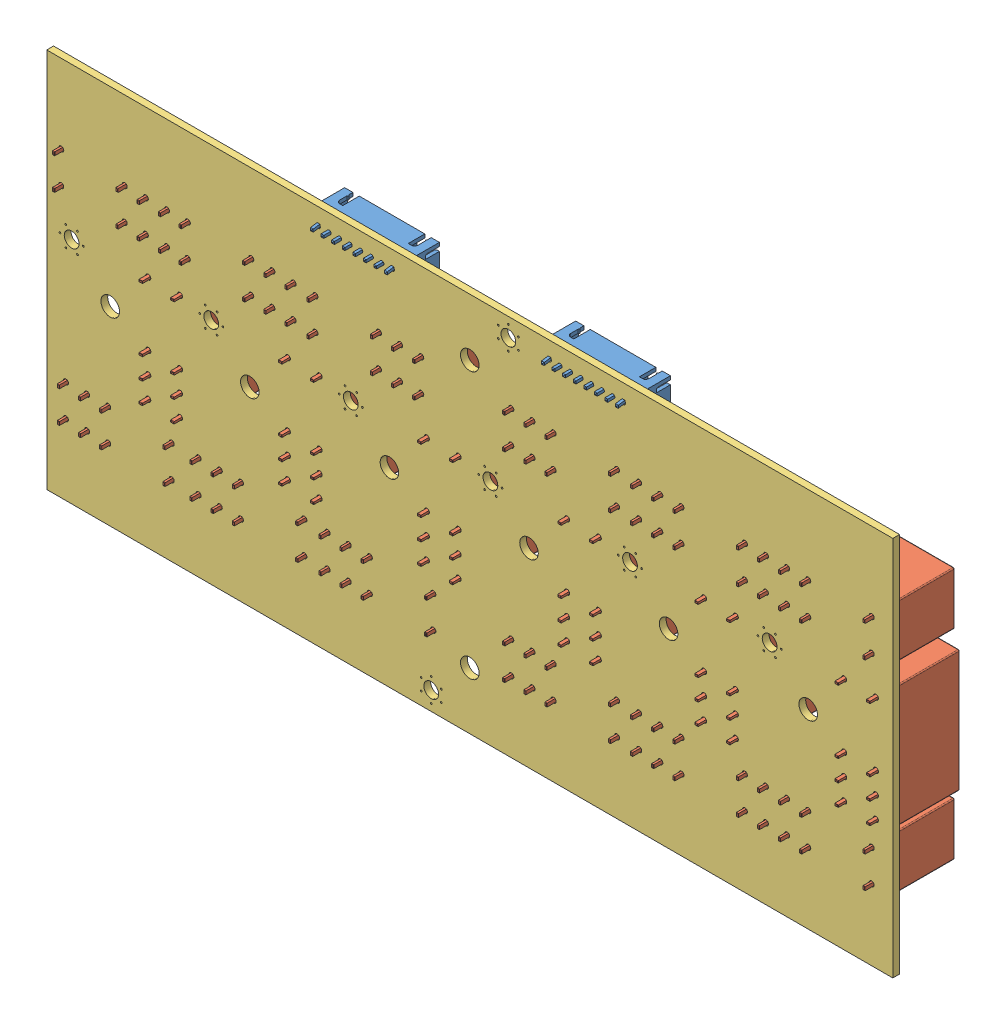
SolidWorks assembly AntennaSwitch_6x2_RelayBoard, configuration 默认. Lengths in mm.
Overall size (200 90 19.2).
42 component instances, 3 part files, 0 mates.
Components (placement in the parent):
- 复件 AntennaSwitch_6x2_RelayBoard(2)^AntennaSwitch_6x2_RelayBoard-1: 复件 AntennaSwitch_6x2_RelayBoard(2)^AntennaSwitch_6x2_RelayBoard [默认] at origin size (200 90 19.2) (virtual)
  - JST_XH_B8B-XH-A_1x08_P2.50mm_Vertical^复件 AntennaSwitch_6x2_RelayBoard(2)_AntennaSwitch_6x2_RelayBoard-1: JST_XH_B8B-XH-A_1x08_P2.50mm_Vertical^复件 AntennaSwitch_6x2_RelayBoard(2)_AntennaSwitch_6x2_RelayBoard [默认] at (131.725 -53.983 -0.05) x (-1 0 0) z (0 0 -1) size (22.4 5.75 10.4) (virtual)
    - SOLID^JST_XH_B8B-XH-A_1x08_P2.50mm_Vertical_复件 AntennaSwitch_6x2_RelayBoard(2)_AntennaSwitch_6x2_RelayBoard-1: SOLID^JST_XH_B8B-XH-A_1x08_P2.50mm_Vertical_复件 AntennaSwitch_6x2_RelayBoard(2)_AntennaSwitch_6x2_RelayBoard [默认] at origin size (22.4 5.75 10.4) (virtual)
  - JST_XH_B8B-XH-A_1x08_P2.50mm_Vertical^复件 AntennaSwitch_6x2_RelayBoard(2)_AntennaSwitch_6x2_RelayBoard-2: JST_XH_B8B-XH-A_1x08_P2.50mm_Vertical^复件 AntennaSwitch_6x2_RelayBoard(2)_AntennaSwitch_6x2_RelayBoard [默认] at (186.335 -53.983 -0.05) x (-1 0 0) z (0 0 -1) size (22.4 5.75 10.4) (virtual)
    - SOLID^JST_XH_B8B-XH-A_1x08_P2.50mm_Vertical_复件 AntennaSwitch_6x2_RelayBoard(2)_AntennaSwitch_6x2_RelayBoard-1: SOLID^JST_XH_B8B-XH-A_1x08_P2.50mm_Vertical_复件 AntennaSwitch_6x2_RelayBoard(2)_AntennaSwitch_6x2_RelayBoard [默认] at origin size (22.4 5.75 10.4) (virtual)
  - Relay_DPDT_Omron_G2RL^复件 AntennaSwitch_6x2_RelayBoard(2)_AntennaSwitch_6x2_RelayBoard-1: Relay_DPDT_Omron_G2RL^复件 AntennaSwitch_6x2_RelayBoard(2)_AntennaSwitch_6x2_RelayBoard [默认] at (53.42 -68.554 -0.05) x (1 0 0) z (0 0 -1) size (28.8 12.5 19.2) (virtual)
    - SOLID-0^Relay_DPDT_Omron_G2RL_复件 AntennaSwitch_6x2_RelayBoard(2)_AntennaSwitch_6x2_RelayBoard-1: SOLID-0^Relay_DPDT_Omron_G2RL_复件 AntennaSwitch_6x2_RelayBoard(2)_AntennaSwitch_6x2_RelayBoard [默认] at origin size (28.8 12.5 19.2) (virtual)
  - Relay_DPDT_Omron_G2RL^复件 AntennaSwitch_6x2_RelayBoard(2)_AntennaSwitch_6x2_RelayBoard-2: Relay_DPDT_Omron_G2RL^复件 AntennaSwitch_6x2_RelayBoard(2)_AntennaSwitch_6x2_RelayBoard [默认] at (83.34 -68.554 -0.05) x (1 0 0) z (0 0 -1) size (28.8 12.5 19.2) (virtual)
    - SOLID-0^Relay_DPDT_Omron_G2RL_复件 AntennaSwitch_6x2_RelayBoard(2)_AntennaSwitch_6x2_RelayBoard-1: SOLID-0^Relay_DPDT_Omron_G2RL_复件 AntennaSwitch_6x2_RelayBoard(2)_AntennaSwitch_6x2_RelayBoard [默认] at origin size (28.8 12.5 19.2) (virtual)
  - Relay_DPDT_Omron_G2RL^复件 AntennaSwitch_6x2_RelayBoard(2)_AntennaSwitch_6x2_RelayBoard-3: Relay_DPDT_Omron_G2RL^复件 AntennaSwitch_6x2_RelayBoard(2)_AntennaSwitch_6x2_RelayBoard [默认] at (113.52 -68.554 -0.05) x (1 0 0) z (0 0 -1) size (28.8 12.5 19.2) (virtual)
    - SOLID-0^Relay_DPDT_Omron_G2RL_复件 AntennaSwitch_6x2_RelayBoard(2)_AntennaSwitch_6x2_RelayBoard-1: SOLID-0^Relay_DPDT_Omron_G2RL_复件 AntennaSwitch_6x2_RelayBoard(2)_AntennaSwitch_6x2_RelayBoard [默认] at origin size (28.8 12.5 19.2) (virtual)
  - Relay_DPDT_Omron_G2RL^复件 AntennaSwitch_6x2_RelayBoard(2)_AntennaSwitch_6x2_RelayBoard-4: Relay_DPDT_Omron_G2RL^复件 AntennaSwitch_6x2_RelayBoard(2)_AntennaSwitch_6x2_RelayBoard [默认] at (184.811 -76 -0.05) x (-1 0 0) z (0 0 -1) size (28.8 12.5 19.2) (virtual)
    - SOLID-0^Relay_DPDT_Omron_G2RL_复件 AntennaSwitch_6x2_RelayBoard(2)_AntennaSwitch_6x2_RelayBoard-1: SOLID-0^Relay_DPDT_Omron_G2RL_复件 AntennaSwitch_6x2_RelayBoard(2)_AntennaSwitch_6x2_RelayBoard [默认] at origin size (28.8 12.5 19.2) (virtual)
  - Relay_DPDT_Omron_G2RL^复件 AntennaSwitch_6x2_RelayBoard(2)_AntennaSwitch_6x2_RelayBoard-5: Relay_DPDT_Omron_G2RL^复件 AntennaSwitch_6x2_RelayBoard(2)_AntennaSwitch_6x2_RelayBoard [默认] at (215.037 -76 -0.05) x (-1 0 0) z (0 0 -1) size (28.8 12.5 19.2) (virtual)
    - SOLID-0^Relay_DPDT_Omron_G2RL_复件 AntennaSwitch_6x2_RelayBoard(2)_AntennaSwitch_6x2_RelayBoard-1: SOLID-0^Relay_DPDT_Omron_G2RL_复件 AntennaSwitch_6x2_RelayBoard(2)_AntennaSwitch_6x2_RelayBoard [默认] at origin size (28.8 12.5 19.2) (virtual)
  - Relay_DPDT_Omron_G2RL^复件 AntennaSwitch_6x2_RelayBoard(2)_AntennaSwitch_6x2_RelayBoard-6: Relay_DPDT_Omron_G2RL^复件 AntennaSwitch_6x2_RelayBoard(2)_AntennaSwitch_6x2_RelayBoard [默认] at (245.009 -76 -0.05) x (-1 0 0) z (0 0 -1) size (28.8 12.5 19.2) (virtual)
    - SOLID-0^Relay_DPDT_Omron_G2RL_复件 AntennaSwitch_6x2_RelayBoard(2)_AntennaSwitch_6x2_RelayBoard-1: SOLID-0^Relay_DPDT_Omron_G2RL_复件 AntennaSwitch_6x2_RelayBoard(2)_AntennaSwitch_6x2_RelayBoard [默认] at origin size (28.8 12.5 19.2) (virtual)
  - Relay_DPDT_Omron_G2RL^复件 AntennaSwitch_6x2_RelayBoard(2)_AntennaSwitch_6x2_RelayBoard-7: Relay_DPDT_Omron_G2RL^复件 AntennaSwitch_6x2_RelayBoard(2)_AntennaSwitch_6x2_RelayBoard [默认] at (81.5 -84.5 -0.05) x (0 -1 0) z (0 0 -1) size (28.8 12.5 19.2) (virtual)
    - SOLID-0^Relay_DPDT_Omron_G2RL_复件 AntennaSwitch_6x2_RelayBoard(2)_AntennaSwitch_6x2_RelayBoard-1: SOLID-0^Relay_DPDT_Omron_G2RL_复件 AntennaSwitch_6x2_RelayBoard(2)_AntennaSwitch_6x2_RelayBoard [默认] at origin size (28.8 12.5 19.2) (virtual)
  - Relay_DPDT_Omron_G2RL^复件 AntennaSwitch_6x2_RelayBoard(2)_AntennaSwitch_6x2_RelayBoard-8: Relay_DPDT_Omron_G2RL^复件 AntennaSwitch_6x2_RelayBoard(2)_AntennaSwitch_6x2_RelayBoard [默认] at (114.5 -84.5 -0.05) x (0 -1 0) z (0 0 -1) size (28.8 12.5 19.2) (virtual)
    - SOLID-0^Relay_DPDT_Omron_G2RL_复件 AntennaSwitch_6x2_RelayBoard(2)_AntennaSwitch_6x2_RelayBoard-1: SOLID-0^Relay_DPDT_Omron_G2RL_复件 AntennaSwitch_6x2_RelayBoard(2)_AntennaSwitch_6x2_RelayBoard [默认] at origin size (28.8 12.5 19.2) (virtual)
  - Relay_DPDT_Omron_G2RL^复件 AntennaSwitch_6x2_RelayBoard(2)_AntennaSwitch_6x2_RelayBoard-9: Relay_DPDT_Omron_G2RL^复件 AntennaSwitch_6x2_RelayBoard(2)_AntennaSwitch_6x2_RelayBoard [默认] at (147.353 -84.5 -0.05) x (0 -1 0) z (0 0 -1) size (28.8 12.5 19.2) (virtual)
    - SOLID-0^Relay_DPDT_Omron_G2RL_复件 AntennaSwitch_6x2_RelayBoard(2)_AntennaSwitch_6x2_RelayBoard-1: SOLID-0^Relay_DPDT_Omron_G2RL_复件 AntennaSwitch_6x2_RelayBoard(2)_AntennaSwitch_6x2_RelayBoard [默认] at origin size (28.8 12.5 19.2) (virtual)
  - Relay_DPDT_Omron_G2RL^复件 AntennaSwitch_6x2_RelayBoard(2)_AntennaSwitch_6x2_RelayBoard-10: Relay_DPDT_Omron_G2RL^复件 AntennaSwitch_6x2_RelayBoard(2)_AntennaSwitch_6x2_RelayBoard [默认] at (180.5 -84.5 -0.05) x (0 -1 0) z (0 0 -1) size (28.8 12.5 19.2) (virtual)
    - SOLID-0^Relay_DPDT_Omron_G2RL_复件 AntennaSwitch_6x2_RelayBoard(2)_AntennaSwitch_6x2_RelayBoard-1: SOLID-0^Relay_DPDT_Omron_G2RL_复件 AntennaSwitch_6x2_RelayBoard(2)_AntennaSwitch_6x2_RelayBoard [默认] at origin size (28.8 12.5 19.2) (virtual)
  - Relay_DPDT_Omron_G2RL^复件 AntennaSwitch_6x2_RelayBoard(2)_AntennaSwitch_6x2_RelayBoard-11: Relay_DPDT_Omron_G2RL^复件 AntennaSwitch_6x2_RelayBoard(2)_AntennaSwitch_6x2_RelayBoard [默认] at (212.885 -84.5 -0.05) x (0 -1 0) z (0 0 -1) size (28.8 12.5 19.2) (virtual)
    - SOLID-0^Relay_DPDT_Omron_G2RL_复件 AntennaSwitch_6x2_RelayBoard(2)_AntennaSwitch_6x2_RelayBoard-1: SOLID-0^Relay_DPDT_Omron_G2RL_复件 AntennaSwitch_6x2_RelayBoard(2)_AntennaSwitch_6x2_RelayBoard [默认] at origin size (28.8 12.5 19.2) (virtual)
  - Relay_DPDT_Omron_G2RL^复件 AntennaSwitch_6x2_RelayBoard(2)_AntennaSwitch_6x2_RelayBoard-12: Relay_DPDT_Omron_G2RL^复件 AntennaSwitch_6x2_RelayBoard(2)_AntennaSwitch_6x2_RelayBoard [默认] at (246 -84.5 -0.05) x (0 -1 0) z (0 0 -1) size (28.8 12.5 19.2) (virtual)
    - SOLID-0^Relay_DPDT_Omron_G2RL_复件 AntennaSwitch_6x2_RelayBoard(2)_AntennaSwitch_6x2_RelayBoard-1: SOLID-0^Relay_DPDT_Omron_G2RL_复件 AntennaSwitch_6x2_RelayBoard(2)_AntennaSwitch_6x2_RelayBoard [默认] at origin size (28.8 12.5 19.2) (virtual)
  - Relay_DPDT_Omron_G2RL^复件 AntennaSwitch_6x2_RelayBoard(2)_AntennaSwitch_6x2_RelayBoard-13: Relay_DPDT_Omron_G2RL^复件 AntennaSwitch_6x2_RelayBoard(2)_AntennaSwitch_6x2_RelayBoard [默认] at (79.528 -123.213 -0.05) x (-1 0 0) z (0 0 -1) size (28.8 12.5 19.2) (virtual)
    - SOLID-0^Relay_DPDT_Omron_G2RL_复件 AntennaSwitch_6x2_RelayBoard(2)_AntennaSwitch_6x2_RelayBoard-1: SOLID-0^Relay_DPDT_Omron_G2RL_复件 AntennaSwitch_6x2_RelayBoard(2)_AntennaSwitch_6x2_RelayBoard [默认] at origin size (28.8 12.5 19.2) (virtual)
  - Relay_DPDT_Omron_G2RL^复件 AntennaSwitch_6x2_RelayBoard(2)_AntennaSwitch_6x2_RelayBoard-14: Relay_DPDT_Omron_G2RL^复件 AntennaSwitch_6x2_RelayBoard(2)_AntennaSwitch_6x2_RelayBoard [默认] at (110.897 -123.086 -0.05) x (-1 0 0) z (0 0 -1) size (28.8 12.5 19.2) (virtual)
    - SOLID-0^Relay_DPDT_Omron_G2RL_复件 AntennaSwitch_6x2_RelayBoard(2)_AntennaSwitch_6x2_RelayBoard-1: SOLID-0^Relay_DPDT_Omron_G2RL_复件 AntennaSwitch_6x2_RelayBoard(2)_AntennaSwitch_6x2_RelayBoard [默认] at origin size (28.8 12.5 19.2) (virtual)
  - Relay_DPDT_Omron_G2RL^复件 AntennaSwitch_6x2_RelayBoard(2)_AntennaSwitch_6x2_RelayBoard-15: Relay_DPDT_Omron_G2RL^复件 AntennaSwitch_6x2_RelayBoard(2)_AntennaSwitch_6x2_RelayBoard [默认] at (141.377 -123.086 -0.05) x (-1 0 0) z (0 0 -1) size (28.8 12.5 19.2) (virtual)
    - SOLID-0^Relay_DPDT_Omron_G2RL_复件 AntennaSwitch_6x2_RelayBoard(2)_AntennaSwitch_6x2_RelayBoard-1: SOLID-0^Relay_DPDT_Omron_G2RL_复件 AntennaSwitch_6x2_RelayBoard(2)_AntennaSwitch_6x2_RelayBoard [默认] at origin size (28.8 12.5 19.2) (virtual)
  - Relay_DPDT_Omron_G2RL^复件 AntennaSwitch_6x2_RelayBoard(2)_AntennaSwitch_6x2_RelayBoard-16: Relay_DPDT_Omron_G2RL^复件 AntennaSwitch_6x2_RelayBoard(2)_AntennaSwitch_6x2_RelayBoard [默认] at (184.811 -123.213 -0.05) x (-1 0 0) z (0 0 -1) size (28.8 12.5 19.2) (virtual)
    - SOLID-0^Relay_DPDT_Omron_G2RL_复件 AntennaSwitch_6x2_RelayBoard(2)_AntennaSwitch_6x2_RelayBoard-1: SOLID-0^Relay_DPDT_Omron_G2RL_复件 AntennaSwitch_6x2_RelayBoard(2)_AntennaSwitch_6x2_RelayBoard [默认] at origin size (28.8 12.5 19.2) (virtual)
  - Relay_DPDT_Omron_G2RL^复件 AntennaSwitch_6x2_RelayBoard(2)_AntennaSwitch_6x2_RelayBoard-17: Relay_DPDT_Omron_G2RL^复件 AntennaSwitch_6x2_RelayBoard(2)_AntennaSwitch_6x2_RelayBoard [默认] at (215.037 -123.213 -0.05) x (-1 0 0) z (0 0 -1) size (28.8 12.5 19.2) (virtual)
    - SOLID-0^Relay_DPDT_Omron_G2RL_复件 AntennaSwitch_6x2_RelayBoard(2)_AntennaSwitch_6x2_RelayBoard-1: SOLID-0^Relay_DPDT_Omron_G2RL_复件 AntennaSwitch_6x2_RelayBoard(2)_AntennaSwitch_6x2_RelayBoard [默认] at origin size (28.8 12.5 19.2) (virtual)
  - Relay_DPDT_Omron_G2RL^复件 AntennaSwitch_6x2_RelayBoard(2)_AntennaSwitch_6x2_RelayBoard-18: Relay_DPDT_Omron_G2RL^复件 AntennaSwitch_6x2_RelayBoard(2)_AntennaSwitch_6x2_RelayBoard [默认] at (245.009 -123.213 -0.05) x (-1 0 0) z (0 0 -1) size (28.8 12.5 19.2) (virtual)
    - SOLID-0^Relay_DPDT_Omron_G2RL_复件 AntennaSwitch_6x2_RelayBoard(2)_AntennaSwitch_6x2_RelayBoard-1: SOLID-0^Relay_DPDT_Omron_G2RL_复件 AntennaSwitch_6x2_RelayBoard(2)_AntennaSwitch_6x2_RelayBoard [默认] at origin size (28.8 12.5 19.2) (virtual)
  - COMPOUND^复件 AntennaSwitch_6x2_RelayBoard(2)_AntennaSwitch_6x2_RelayBoard-1: COMPOUND^复件 AntennaSwitch_6x2_RelayBoard(2)_AntennaSwitch_6x2_RelayBoard [默认] at origin size (200 90 1.6) (virtual)
